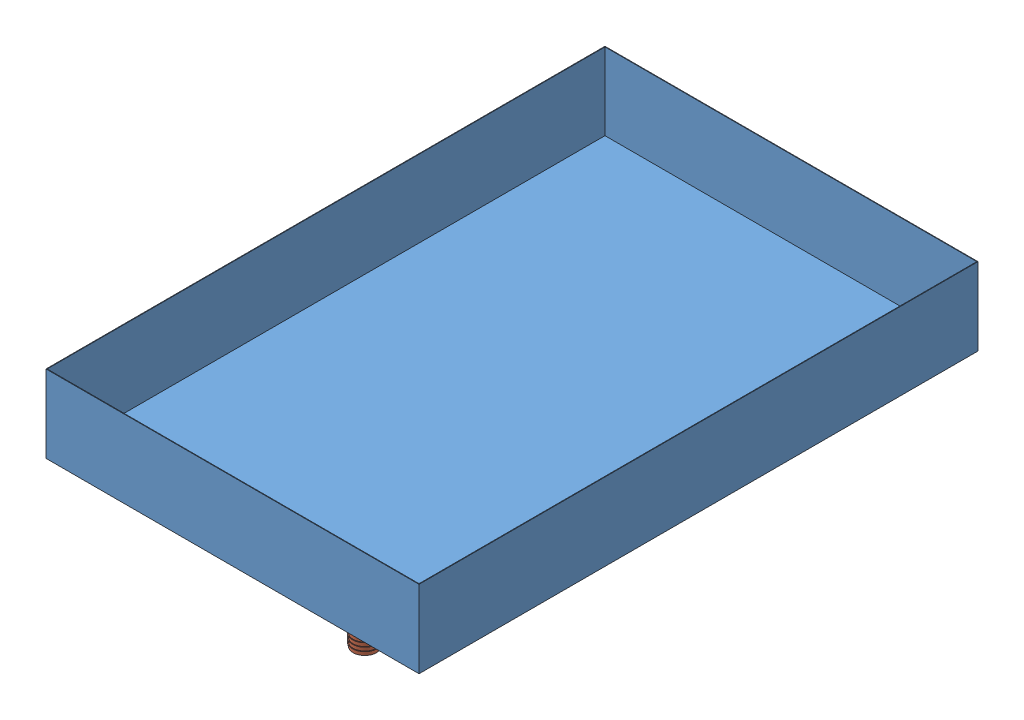
SolidWorks assembly upper tank, configuration Default. Lengths in mm.
Overall size (481.5 154 721.5).
2 component instances, 2 part files, 1 mates.
Components (placement in the parent):
- upper tank body-1: upper tank body [Default] at (243.8486 362.3857 548.4929) size (481.5 100 721.5)
- DN32 pagoda joint-1: DN32 pagoda joint [Default] at (364.5986 308.3857 859.2429) size (32 54 32)
Mates (geometry in assembly coordinates):
- ProfileCenter1: profile center aligned: circle of DN32 pagoda joint-1; circle of upper tank body-1
